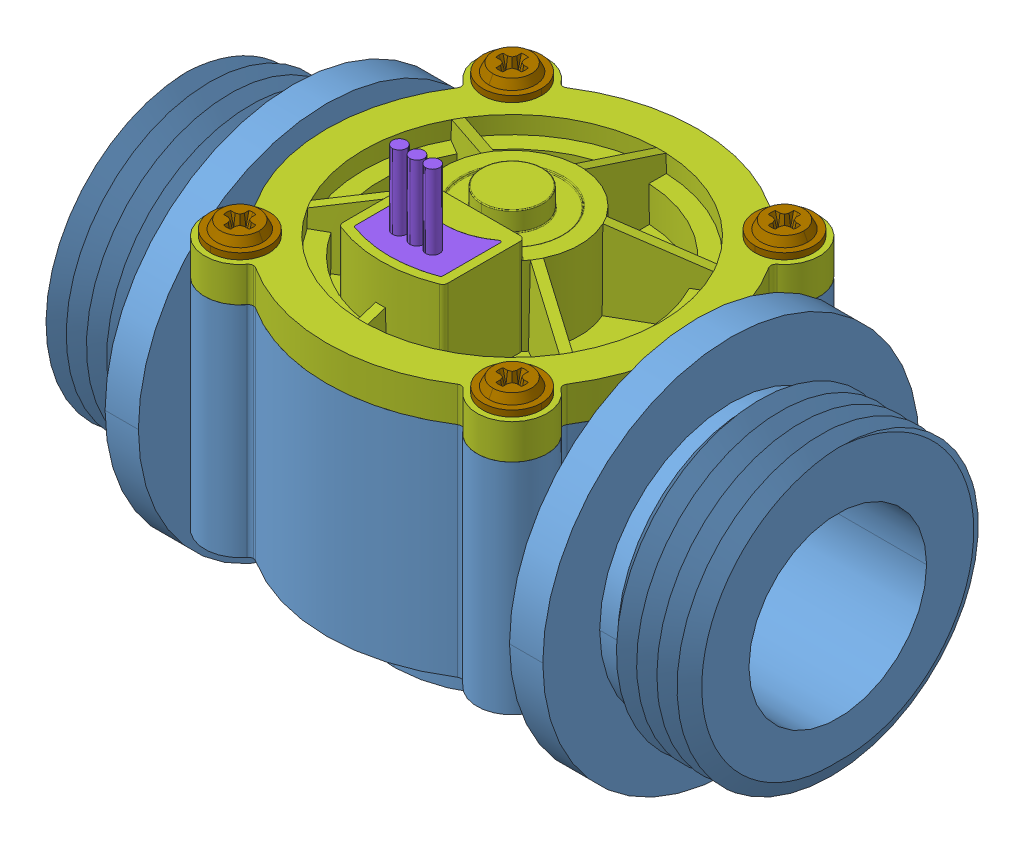
SolidWorks assembly FS400A G1, Water Flow Meter.STEP, configuration Default. Lengths in mm.
Overall size (74.41 54 43).
12 component instances, 9 part files, 0 mates.
Components (placement in the parent):
- Main Body, FS400A G1, Water Flow Meter.STEP-1: Main Body, FS400A G1, Water Flow Meter.STEP [Default] at origin size (74.41 43 43)
- Impeller Shaft, FS400A G1, Water Flow Meter.STEP-1: Impeller Shaft, FS400A G1, Water Flow Meter.STEP [Default] at (0 -14.5 0) x (-1 0 0) z (0 0 -1) size (2.5 32 2.5)
- Flow Meter Impeller, FS400A G1, Water Flow Meter.STEP-1: Flow Meter Impeller, FS400A G1, Water Flow Meter.STEP [Default] at (0 -5.9 0) x (-0.970544 0 -0.240922) z (0.240922 0 -0.970544) size (21.61 20.4 21.61)
- Magnet, Hall Effect Sensor, FS400A G1, Water Flow Meter.STEP-1: Magnet, Hall Effect Sensor, FS400A G1, Water Flow Meter.STEP [Default] at (0 9.1 0) x (-0.970544 0 -0.240922) z (0.240922 0 -0.970544) size (9.8 3.5 9.8)
- Cover Plate, Flow Meter Impeller, FS400A G1, Water Flow Meter.STEP-1: Cover Plate, Flow Meter Impeller, FS400A G1, Water Flow Meter.STEP [Default] at (0 8.2 0) x (0 0 -1) z (1 0 0) size (33.95 5.6 33.95)
- Sealing O-Ring, FS400A G1, Water Flow Meter.STEP-1: Sealing O-Ring, FS400A G1, Water Flow Meter.STEP [Default] at (0 10.05 0) size (36.6 1.9 36.6)
- Cover Plate, FS400A G1, Water Flow Meter.STEP-1: Cover Plate, FS400A G1, Water Flow Meter.STEP [Default] at (0 12.5 0) size (42.4 13.3 42.4)
- Three Wire Connector, FS400A G1, Water Flow Meter.STEP-1: Three Wire Connector, FS400A G1, Water Flow Meter.STEP [Default] at (0 16 10.875) size (10 19.5 7.86)
- M3 X 14, SS Pan Head Self Tapping Screw, FS400A G1, Water Flow Meter_DEFAULT.STEP-1: M3 X 14, SS Pan Head Self Tapping Screw, FS400A G1, Water Flow Meter_DEFAULT.STEP [Default] at (-15.5563 16.5 -15.5563) x (1 0 0) z (0 1 0) size (6.7 6.7 15.6)
- M3 X 14, SS Pan Head Self Tapping Screw, FS400A G1, Water Flow Meter_DEFAULT.STEP-2: M3 X 14, SS Pan Head Self Tapping Screw, FS400A G1, Water Flow Meter_DEFAULT.STEP [Default] at (15.5563 16.5 -15.5563) x (0 0 1) z (0 1 0) size (6.7 6.7 15.6)
- M3 X 14, SS Pan Head Self Tapping Screw, FS400A G1, Water Flow Meter_DEFAULT.STEP-3: M3 X 14, SS Pan Head Self Tapping Screw, FS400A G1, Water Flow Meter_DEFAULT.STEP [Default] at (15.5563 16.5 15.5563) x (-1 0 0) z (0 1 0) size (6.7 6.7 15.6)
- M3 X 14, SS Pan Head Self Tapping Screw, FS400A G1, Water Flow Meter_DEFAULT.STEP-4: M3 X 14, SS Pan Head Self Tapping Screw, FS400A G1, Water Flow Meter_DEFAULT.STEP [Default] at (-15.5563 16.5 15.5563) x (0 0 -1) z (0 1 0) size (6.7 6.7 15.6)
